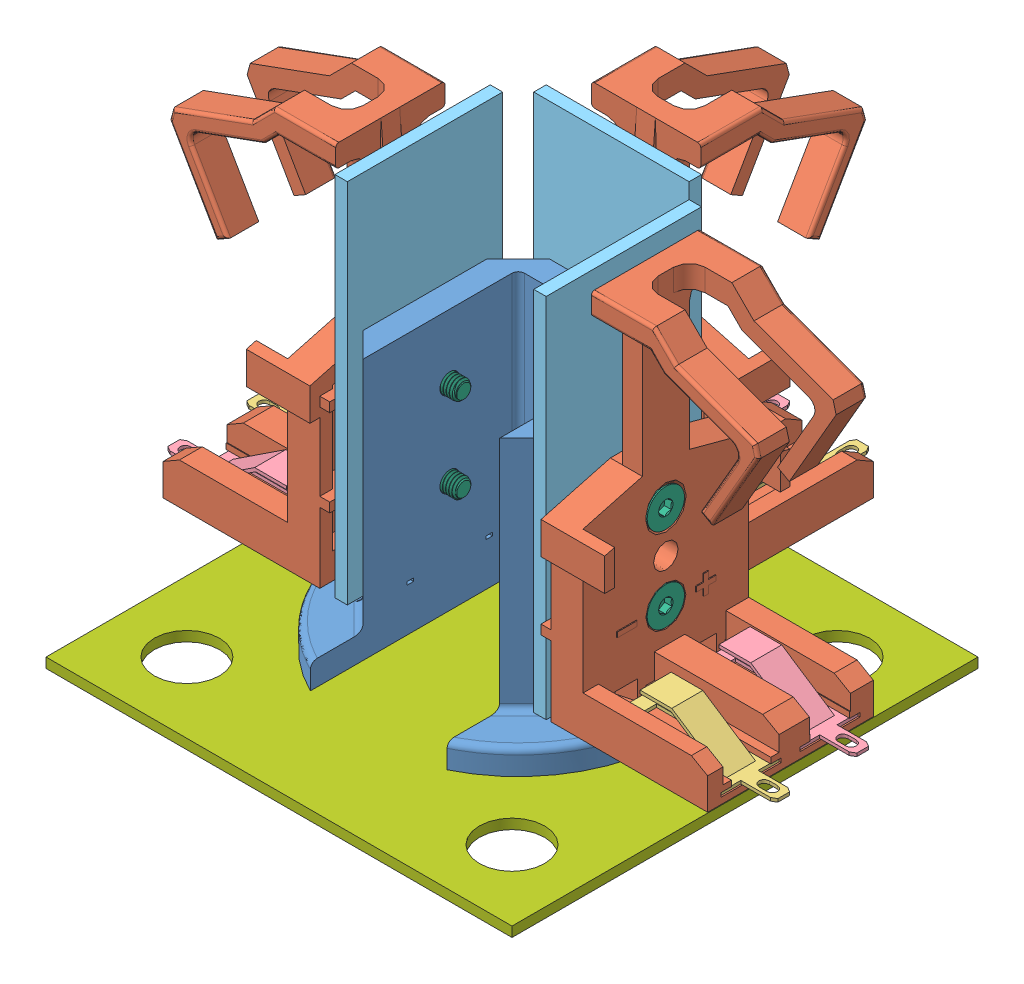
SolidWorks assembly Assembly Concept, configuration Default. Lengths in mm.
Overall size (98.18 66.2 88.09).
23 component instances, 7 part files, 33 mates.
Components (placement in the parent):
- HolderBlock - Copy-1: HolderBlock - Copy [Default] at (14.4282 18.1238 67.1337) size (50 42 47.53)
- bx0033-1: bx0033 [Default] at (10.8282 20.0538 52.1337) x (0 0 -1) z (0 1 0) size (29.85 36.83 58.82)
  - bx0033_01-1: bx0033_01 [Default] at origin size (29.85 30.4 58.82)
  - bx0033_02-1: bx0033_02 [Default] at origin size (9.53 36.83 6.65)
  - bx0033_03-1: bx0033_03 [Default] at origin size (9.53 36.83 6.65)
- 9V PCB-1: 9V PCB [Default] at (12.4282 36.0194 39.6337) size (2 59 25)
- 9V PCB-2: 9V PCB [Default] at (41.9282 36.0194 35.1337) x (0 0 1) z (-1 0 0) size (2 59 25)
- bx0033-2: bx0033 [Default] at (29.4282 20.0538 33.5337) x (1 0 0) z (0 1 0) size (29.85 36.83 58.82)
  - bx0033_01-1: bx0033_01 [Default] at origin size (29.85 30.4 58.82)
  - bx0033_02-1: bx0033_02 [Default] at origin size (9.53 36.83 6.65)
  - bx0033_03-1: bx0033_03 [Default] at origin size (9.53 36.83 6.65)
- 9V PCB-3: 9V PCB [Default] at (46.4282 36.0194 64.6337) x (-1 0 0) z (0 0 -1) size (2 59 25)
- bx0033-3: bx0033 [Default] at (48.0282 20.0538 52.1337) x (0 0 1) z (0 1 0) size (29.85 36.83 58.82)
  - bx0033_01-1: bx0033_01 [Default] at origin size (29.85 30.4 58.82)
  - bx0033_02-1: bx0033_02 [Default] at origin size (9.53 36.83 6.65)
  - bx0033_03-1: bx0033_03 [Default] at origin size (9.53 36.83 6.65)
- BatteryHolder_M3-1: BatteryHolder_M3 [92125A103] at (29.4282 32.1238 28.3737) x (-1 0 0) z (0 0 -1) size (6 6 15.33)
- BatteryHolder_M3-2: BatteryHolder_M3 [92125A103] at (29.4282 45.7838 28.3737) x (-1 0 0) z (0 0 -1) size (6 6 15.33)
- BatteryHolder_M3-3: BatteryHolder_M3 [92125A103] at (5.6682 32.1238 52.1337) x (0 0 1) z (-1 0 0) size (6 6 15.33)
- BatteryHolder_M3-4: BatteryHolder_M3 [92125A103] at (5.6682 45.7838 52.1337) x (0 0.924225 0.381849) z (-1 0 0) size (6 6 15.33)
- BatteryHolder_M3-5: BatteryHolder_M3 [92125A103] at (53.1882 32.1238 52.1337) x (0 0 -1) z (1 0 0) size (6 6 15.33)
- BatteryHolder_M3-6: BatteryHolder_M3 [92125A103] at (53.1882 45.7838 52.1337) x (0 -0.924225 -0.381849) z (1 0 0) size (6 6 15.33)
- NFPA_GeneralPCB_AvionicsBay_V1-1: NFPA_GeneralPCB_AvionicsBay_V1 [Default] at (29.9282 12.5238 53.6337) size (75 1.6 75)
Mates (geometry in assembly coordinates):
- Parallel1: parallel aligned: plane of HolderBlock - Copy-1 through (29.4282 14.1238 52.1337) normal (0 -1 0); plane of bx0033-1/bx0033_01-1 through (10.8282 20.0538 52.1337) normal (0 -1 0)
- Concentric3: concentric anti-aligned: circle of bx0033-1/bx0033_01-1; circle of 9V PCB-1
- Coincident8: coincident anti-aligned: plane of bx0033-1/bx0033_01-1 through (12.4282 20.0538 52.1337) normal (1 0 0); plane of 9V PCB-1 through (12.4282 36.0194 39.6337) normal (-1 0 0)
- Parallel2: parallel aligned: plane of bx0033-1/bx0033_01-1 through (10.8282 20.0538 52.1337) normal (0 -1 0); plane of 9V PCB-1 through (14.4282 19.1238 64.6337) normal (0 -1 0)
- Concentric5: concentric anti-aligned: circle of HolderBlock - Copy-1; circle of bx0033-1/bx0033_01-1
- Coincident14: coincident anti-aligned: plane of HolderBlock - Copy-1 through (14.4282 80.1238 67.1337) normal (-1 0 0); plane of 9V PCB-1 through (14.4282 36.0194 39.6337) normal (1 0 0)
- Parallel3: parallel aligned: plane of HolderBlock - Copy-1 through (29.4282 14.1238 52.1337) normal (0 -1 0); plane of bx0033-2/bx0033_01-1 through (29.4282 20.0538 33.5337) normal (0 -1 0)
- Parallel4: parallel aligned: plane of 9V PCB-2 through (16.9282 19.1238 37.1337) normal (0 -1 0); plane of bx0033-2/bx0033_01-1 through (29.4282 20.0538 33.5337) normal (0 -1 0)
- Concentric6: concentric anti-aligned: circle of bx0033-2/bx0033_01-1; circle of 9V PCB-2
- Coincident18: coincident anti-aligned: plane of 9V PCB-2 through (41.9282 36.0194 35.1337) normal (0 0 -1); plane of bx0033-2/bx0033_01-1 through (29.4282 20.0538 35.1337) normal (0 0 1)
- Concentric7: concentric aligned: circle of HolderBlock - Copy-1; circle of bx0033-2/bx0033_01-1
- Coincident21: coincident anti-aligned: plane of HolderBlock - Copy-1 through (14.4282 80.1238 37.1337) normal (0 0 -1); plane of 9V PCB-2 through (41.9282 36.0194 37.1337) normal (0 0 1)
- Parallel6: parallel aligned: plane of HolderBlock - Copy-1 through (29.4282 14.1238 52.1337) normal (0 -1 0); plane of bx0033-3/bx0033_01-1 through (48.0282 20.0538 52.1337) normal (0 -1 0)
- Parallel7: parallel aligned: plane of HolderBlock - Copy-1 through (29.4282 14.1238 52.1337) normal (0 -1 0); plane of 9V PCB-3 through (44.4282 19.1238 39.6337) normal (0 -1 0)
- Concentric8: concentric anti-aligned: circle of bx0033-3/bx0033_01-1; circle of 9V PCB-3
- Coincident25: coincident anti-aligned: plane of 9V PCB-3 through (46.4282 36.0194 64.6337) normal (1 0 0); plane of bx0033-3/bx0033_01-1 through (46.4282 20.0538 52.1337) normal (-1 0 0)
- Concentric10: concentric aligned: circle of HolderBlock - Copy-1; circle of bx0033-3/bx0033_01-1
- Coincident29: coincident anti-aligned: plane of HolderBlock - Copy-1 through (44.4282 80.1238 67.1337) normal (1 0 0); plane of 9V PCB-3 through (44.4282 36.0194 64.6337) normal (-1 0 0)
- Concentric11: concentric aligned: circle of HolderBlock - Copy-1; circle of BatteryHolder_M3-6
- Coincident31: coincident aligned: plane of bx0033-3/bx0033_01-1 through (53.1882 20.0538 52.1337) normal (1 0 0); plane of BatteryHolder_M3-6 through (53.1882 45.2111 53.5201) normal (1 0 0)
- Concentric12: concentric anti-aligned: circle of bx0033-3/bx0033_01-1; circle of BatteryHolder_M3-5
- Coincident32: coincident aligned: plane of bx0033-3/bx0033_01-1 through (53.1882 20.0538 52.1337) normal (1 0 0); plane of BatteryHolder_M3-5 through (53.1882 30.6238 52.1337) normal (1 0 0)
- Concentric13: concentric anti-aligned: circle of bx0033-2/bx0033_01-1; circle of BatteryHolder_M3-1
- Coincident33: coincident aligned: plane of bx0033-2/bx0033_01-1 through (29.4282 20.0538 28.3737) normal (0 0 -1); plane of BatteryHolder_M3-1 through (29.4282 30.6238 28.3737) normal (0 0 -1)
- Concentric15: concentric anti-aligned: circle of bx0033-1/bx0033_01-1; circle of BatteryHolder_M3-3
- Coincident35: coincident aligned: plane of bx0033-1/bx0033_01-1 through (5.6682 20.0538 52.1337) normal (-1 0 0); plane of BatteryHolder_M3-3 through (5.6682 30.6238 52.1337) normal (-1 0 0)
- Concentric16: concentric anti-aligned: circle of BatteryHolder_M3-4; circle of HolderBlock - Copy-1
- Coincident36: coincident aligned: plane of bx0033-1/bx0033_01-1 through (5.6682 20.0538 52.1337) normal (-1 0 0); plane of BatteryHolder_M3-4 through (5.6682 45.2111 53.5201) normal (-1 0 0)
- Coincident37: coincident anti-aligned: plane of HolderBlock - Copy-1 through (29.4282 14.1238 52.1337) normal (0 -1 0); plane of NFPA_GeneralPCB_AvionicsBay_V1-1 through (29.9282 14.1238 53.6337) normal (0 1 0)
- Distance1: distance = 26 mm: line of NFPA_GeneralPCB_AvionicsBay_V1-1 through (-7.5718 14.1238 16.1337) axis (0 0 1); line of HolderBlock - Copy-1 through (18.4282 14.1238 74.5837) axis (0 0 -1)
- Distance2: distance = 50 mm: line of NFPA_GeneralPCB_AvionicsBay_V1-1 through (-7.5718 14.1238 91.1337) axis (1 0 0); line of HolderBlock - Copy-1 through (19.4282 14.1238 41.1337) axis (1 0 0)
- Concentric17: concentric aligned: circle of HolderBlock - Copy-1; circle of BatteryHolder_M3-2
- Coincident38: coincident aligned: plane of bx0033-2/bx0033_01-1 through (29.4282 20.0538 28.3737) normal (0 0 -1); plane of BatteryHolder_M3-2 through (29.4282 44.2838 28.3737) normal (0 0 -1)
